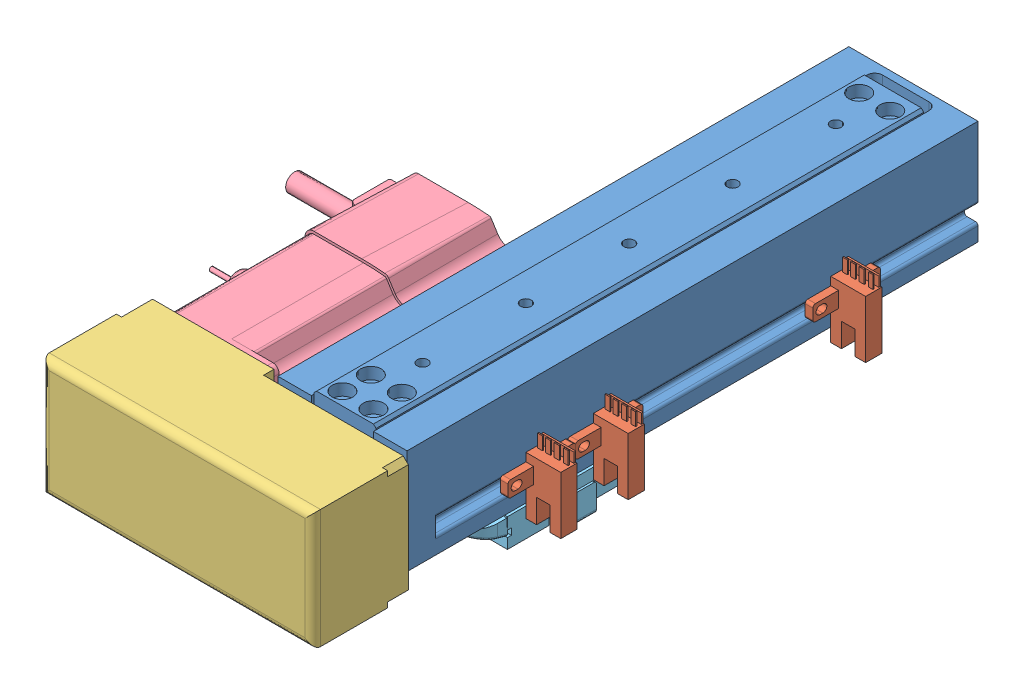
SolidWorks assembly S5M-BL-100W, configuration 默认. Lengths in mm.
Overall size (150.7 54 258).
7 component instances, 5 part files, 24 mates.
Components (placement in the parent):
- S5-BL-导轨^S5M-BL-100W-1: S5-BL-导轨^S5M-BL-100W [默认] x (-1 0 0) z (0 0 -1) size (50 42.7 221) (virtual)
- 传感器^S5M-BL-100W-3: 传感器^S5M-BL-100W [默认] at (31.75 -27.6 -169.3) size (13.5 27.2 26.1) (virtual)
- 传感器^S5M-BL-100W-5: 传感器^S5M-BL-100W [默认] at (31.75 -27.6 -77.4) size (13.5 27.2 26.1) (virtual)
- 传感器^S5M-BL-100W-6: 传感器^S5M-BL-100W [默认] at (31.75 -27.6 -51.3) size (13.5 27.2 26.1) (virtual)
- S5-BL-42M电机安装板^S5M-BL-100W-1: S5-BL-42M电机安装板^S5M-BL-100W [默认] at (-27 -18.4 -3) size (105 46 41) (virtual)
- 100W 电机^S5M-BL-100W-1: 100W 电机^S5M-BL-100W [默认] at (-53.5 -18.4 -59) x (0 1 0) z (0 0 -1) size (42.54 79.97 121.5) (virtual)
- S5-BC-滑块组件^S5M-BL-100W-1: S5-BC-滑块组件^S5M-BL-100W [Default] at (16.8713 -4.7727 -13.8624) x (1 0 0) z (0 0 -1) size (57.33 40 73.16) (virtual)
Mates (geometry in assembly coordinates):
- 重合144: coincident: plane of 传感器^S5M-BL-100W-3 through (25 -38.7 -163) normal (0 -1 0); plane of 传感器^S5M-BL-100W-6 through (25 -38.7 -45) normal (0 -1 0)
- 重合148: coincident: plane of 传感器^S5M-BL-100W-6 through (25 -38.7 -45) normal (0 -1 0); plane of 传感器^S5M-BL-100W-5 through (25 -38.7 -71.1) normal (0 -1 0)
- 距离28: distance = 19.8 mm: plane of 传感器^S5M-BL-100W-6 through (38.5 -16.5 -51.3) normal (0 0 -1); plane of 传感器^S5M-BL-100W-5 through (38.5 -16.5 -71.1) normal (0 0 1)
- 同心299: concentric: cylinder of S5-BL-42M电机安装板^S5M-BL-100W-1 through (-53.5 -18.4 -11) axis (0 0 1) radius 8; cylinder of 100W 电机^S5M-BL-100W-1 through (-53.5 -18.4 -3) axis (0 0 1) radius 4
- 重合176: coincident: plane of S5-BL-42M电机安装板^S5M-BL-100W-1 through (25.5 4.6 -3) normal (0 0 -1); plane of 100W 电机^S5M-BL-100W-1 through (-53.5086 -18.4197 -3) normal (0 0 1)
- 平行1: parallel: plane of S5-BL-42M电机安装板^S5M-BL-100W-1 through (-79.5 -41.4 9) normal (-1 0 0); plane of 100W 电机^S5M-BL-100W-1 through (-73.5 -30.5 -59) normal (-1 0 0)
- 重合188: coincident: plane of 传感器^S5M-BL-100W-3 through (25 -38.7 -163) normal (-1 0 0); plane of 传感器^S5M-BL-100W-5 through (25 -38.7 -71.1) normal (-1 0 0)
- 重合189: coincident: plane of 传感器^S5M-BL-100W-5 through (25 -38.7 -71.1) normal (-1 0 0); plane of 传感器^S5M-BL-100W-6 through (25 -38.7 -45) normal (-1 0 0)
- 重合190: coincident: plane of 传感器^S5M-BL-100W-5 through (25 -16.5 -71.1) normal (0 1 0); plane of 传感器^S5M-BL-100W-6 through (25 -16.5 -45) normal (0 1 0)
- 重合191: coincident: plane of 传感器^S5M-BL-100W-3 through (25 -16.5 -163) normal (0 1 0); plane of 传感器^S5M-BL-100W-6 through (25 -16.5 -45) normal (0 1 0)
- 重合200: coincident: plane of S5-BL-42M电机安装板^S5M-BL-100W-1 through (54.4225 -50.8778 1) normal (0 0 -1); plane of S5-BL-导轨^S5M-BL-100W-1 through (0 0 1) normal (0 0 1)
- 平行9: parallel: plane of S5-BL-42M电机安装板^S5M-BL-100W-1 through (-79.5 4.6 9) normal (0 1 0); plane of S5-BL-导轨^S5M-BL-100W-1 through (-12.5 -34.2 -8) normal (0 -1 0)
- 距离39: distance = 0.5 mm: plane of S5-BL-导轨^S5M-BL-100W-1 through (25 -33.5 -10) normal (1 0 0); plane of S5-BL-42M电机安装板^S5M-BL-100W-1 through (25.5 -41.4 9) normal (1 0 0)
- 距离40: distance = 7.2 mm: plane of S5-BL-42M电机安装板^S5M-BL-100W-1 through (-79.5 -41.4 9) normal (0 -1 0); plane of S5-BL-导轨^S5M-BL-100W-1 through (-12.5 -34.2 -8) normal (0 -1 0)
- 重合209: coincident: plane of 传感器^S5M-BL-100W-3 through (25 -38.7 -163) normal (-1 0 0); plane of S5-BL-导轨^S5M-BL-100W-1 through (25 -33.5 -10) normal (1 0 0)
- 平行16: parallel: plane of 传感器^S5M-BL-100W-3 through (25 -38.7 -163) normal (0 -1 0); plane of S5-BL-导轨^S5M-BL-100W-1 through (0 -33.5 -10) normal (0 -1 0)
- 距离42: distance = 40.8 mm: plane of S5-BL-导轨^S5M-BL-100W-1 through (0 0 -220) normal (0 0 -1); plane of 传感器^S5M-BL-100W-3 through (28 -19.7 -179.2) normal (0 0 -1)
- 距离43: distance = 25 mm: plane of S5-BC-滑块组件^S5M-BL-100W-1; plane of S5-BL-导轨^S5M-BL-100W-1 through (-25 7 -10) normal (-1 0 0)
- 距离44: distance = 54 mm: plane of S5-BC-滑块组件^S5M-BL-100W-1 through (-21 -45.5 -45.8624) normal (0 -1 0); plane of S5-BL-导轨^S5M-BL-100W-1 through (12 8.5 -212) normal (0 1 0)
- 距离46: distance = 25 mm: plane of 传感器^S5M-BL-100W-3 through (25 -16.5 -163) normal (0 1 0); plane of S5-BL-导轨^S5M-BL-100W-1 through (12 8.5 -212) normal (0 1 0)
- 距离47: distance = 73.1 mm: plane of 传感器^S5M-BL-100W-6 through (28 -19.7 -35.1) normal (0 0 1); plane of S5-BL-42M电机安装板^S5M-BL-100W-1 through (-27 -18.4 38) normal (0 0 1)
- 重合210: coincident: plane of S5-BL-导轨^S5M-BL-100W-1 through (0 0 0) normal (-1 0 0); plane of assembly through (0 0 0) normal (1 0 0)
- 重合211: coincident: plane of S5-BL-导轨^S5M-BL-100W-1; plane of assembly through (0 0 0) normal (0 1 0)
- 重合212: coincident: plane of S5-BL-导轨^S5M-BL-100W-1 through (0 0 0) normal (0 0 -1); plane of assembly through (0 0 0) normal (0 0 1)
